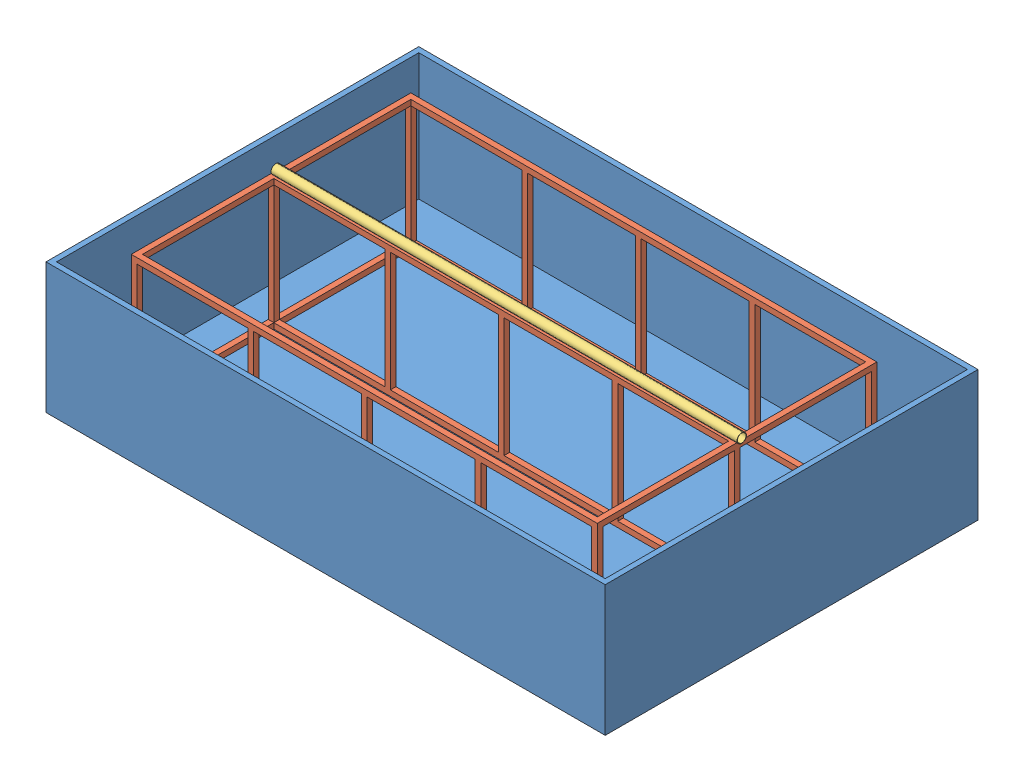
SolidWorks assembly Pool_Asy, configuration Default. Lengths in mm.
Overall size (3000 779 2000).
3 component instances, 3 part files, 2 mates.
Components (placement in the parent):
- Pool-1: Pool [Default] at (-2207.3489 2653.5143 1138.7844) size (3000 700 2000)
- Large_Frame-1: Large_Frame [Default] at (-1993.6963 2673.5143 -604.9352) size (2500 700 1500)
- Straight_pipe-1: Straight_pipe [Default] at (-1977.5796 3398.5143 136.0651) x (1 0 0) z (0 0.873713 -0.486442) size (2500 50 50)
Mates (geometry in assembly coordinates):
- Coincident1: coincident anti-aligned: plane of Pool-1 through (-2207.3489 2673.5143 1138.7844) normal (0 1 0); plane of Large_Frame-1 through (-1993.6963 2673.5143 895.0648) normal (0 -1 0)
- Tangent1: tangent anti-aligned: plane of Large_Frame-1 through (-1993.6963 3373.5143 895.0648) normal (0 1 0); cylinder of Straight_pipe-1 through (522.4204 3398.5143 136.0651) axis (-1 0 0) radius 25
